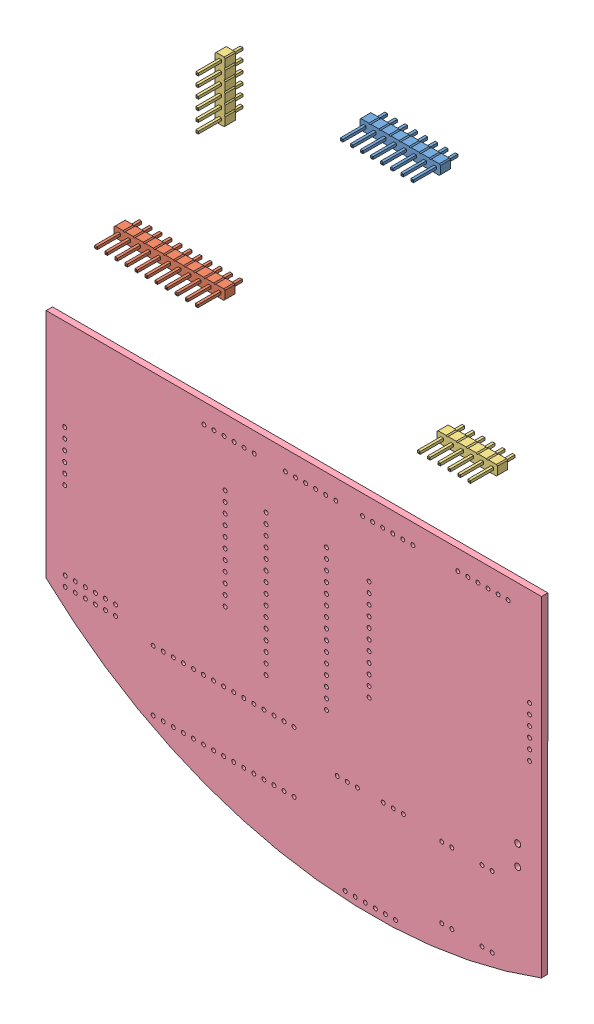
SolidWorks assembly mike_pcb_control, configuration Default. Lengths in mm.
Overall size (125 175.39 11.54).
10 component instances, 4 part files, 0 mates.
Components (placement in the parent):
- mike_pcb_control.step-1: mike_pcb_control.step [Default] at origin size (125 175.39 11.54)
  - PinHeader_2x20_P2.54mm_Vertical.step-1: PinHeader_2x20_P2.54mm_Vertical.step [Default] at (151 -35.5 1.65) x (0 1 0) z (0 0 1) size (2.54 20.32 11.54)
    - SOLID.step-1: SOLID.step [Default] at origin size (2.54 20.32 11.54)
  - PinHeader_1x16_P2.54mm_Vertical.step-1: PinHeader_1x16_P2.54mm_Vertical.step [Default] at (89 -90 1.65) x (0 1 0) z (0 0 1) size (2.54 27.94 11.54)
    - SOLID-0.step-1: SOLID-0.step [Default] at origin size (2.54 27.94 11.54)
  - PinHeader_1x06_P2.54mm_Vertical.step-1: PinHeader_1x06_P2.54mm_Vertical.step [Default] at (114.5 -52 1.65) x (-1 0 0) z (0 0 1) size (2.54 15.24 11.54)
    - SOLID-1.step-1: SOLID-1.step [Default] at origin size (2.54 15.24 11.54)
  - PinHeader_1x06_P2.54mm_Vertical.step-2: PinHeader_1x06_P2.54mm_Vertical.step [Default] at (170.5 -94 1.65) x (0 1 0) z (0 0 1) size (2.54 15.24 11.54)
    - SOLID-1.step-1: SOLID-1.step [Default] at origin size (2.54 15.24 11.54)
  - COMPOUND.step-1: COMPOUND.step [Default] at origin size (125 91.12 1.6)
